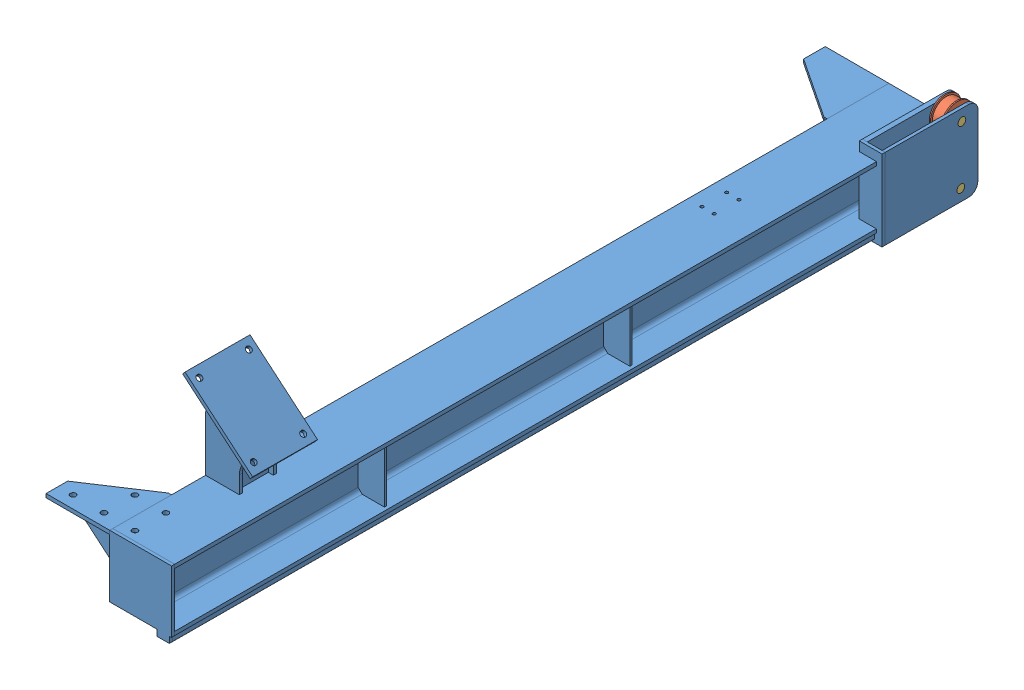
SolidWorks assembly 伸缩内壁装配, configuration 默认. Lengths in mm.
Overall size (424 557.37 2597.83).
9 component instances, 4 part files, 17 mates.
Components (placement in the parent):
- 提升侧内臂-1: 提升侧内臂 [默认<按加工>] at (318.4513 -276.1929 3310.3248) x (1 0 0) z (0 0.003262 0.999995) size (424 530 2590)
- 内套走轮-1: 内套走轮 [默认] at (404.5125 -377.4278 785.6415) x (0 -0.991423 -0.130691) z (0 -0.130691 0.991423) size (100 42 100)
- 内套走轮-2: 内套走轮 [默认] at (403.9866 -191.4386 782.0349) x (0 -0.979148 -0.203148) z (0 -0.203148 0.979148) size (100 42 100)
- 内套轮轴-1: 内套轮轴 [默认] at (158.6099 685.9764 -510.7484) x (1 0 0) z (0 -0.203148 0.979148) size (74 25.13 25.13)
- 内套轮轴-2: 内套轮轴 [默认] at (158.6099 528.967 -486.9912) x (1 0 0) z (0 -0.225215 0.974309) size (74 25.13 25.13)
- deep groove ball bearings gb-1: deep groove ball bearings gb [Rolling bearings 16005 GB 276-94] at (385.9866 -191.4386 782.0349) x (1 0 0) z (0 -0.203148 0.979148) size (8 47 47)
- deep groove ball bearings gb-2: deep groove ball bearings gb [Rolling bearings 16005 GB 276-94] at (418.5125 -377.4278 785.6415) x (1 0 0) z (0 -0.130691 0.991423) size (8 47 47)
- deep groove ball bearings gb-3: deep groove ball bearings gb [Rolling bearings 16005 GB 276-94] at (386.5125 -377.4278 785.6415) x (1 0 0) z (0 -0.130691 0.991423) size (8 47 47)
- deep groove ball bearings gb-4: deep groove ball bearings gb [Rolling bearings 16005 GB 276-94] at (417.9866 -191.4386 782.0349) x (1 0 0) z (0 -0.203148 0.979148) size (8 47 47)
Mates (geometry in assembly coordinates):
- 平行1: parallel: plane of 提升侧内臂-1 through (426.4513 -714.0533 1031.7408) normal (-1 0 0); plane of 内套走轮-2 through (422.9866 -168.4286 786.8089) normal (1 0 0)
- 平行2: parallel: plane of 提升侧内臂-1 through (426.4513 -714.0533 1031.7408) normal (-1 0 0); plane of 内套走轮-1 through (423.5125 -354.1294 788.7128) normal (1 0 0)
- 同心10: concentric: cylinder of 提升侧内臂-1 through (327.0959 -377.4278 785.6415) axis (1 0 0) radius 12.5; cylinder of 内套轮轴-2 through (326.9056 -377.4278 785.6415) axis (1 0 0) radius 12.5673
- 同心2: concentric: cylinder of 内套走轮-2 through (453.7136 -191.4386 782.0349) axis (1 0 0) radius 23.5; cylinder of deep groove ball bearings gb-1 through (377.276 -191.4386 782.0349) axis (-1 0 0) radius 23.5
- 重合4: coincident: plane of 内套走轮-2 through (389.9866 -173.3244 785.7931) normal (-1 0 0); plane of deep groove ball bearings gb-1 through (389.9866 -168.4286 786.8089) normal (1 0 0)
- 同心3: concentric: cylinder of 内套走轮-2 through (453.7136 -191.4386 782.0349) axis (1 0 0) radius 23.5; cylinder of deep groove ball bearings gb-4 through (409.276 -191.4386 782.0349) axis (-1 0 0) radius 23.5
- 重合5: coincident: plane of 内套走轮-2 through (413.9866 -173.3244 785.7931) normal (1 0 0); plane of deep groove ball bearings gb-4 through (413.9866 -168.4286 786.8089) normal (-1 0 0)
- 同心4: concentric: cylinder of 内套轮轴-1 through (326.9056 -191.4386 782.0349) axis (1 0 0) radius 12.5673; cylinder of deep groove ball bearings gb-4 through (411.0153 -191.4386 782.0349) axis (-1 0 0) radius 12.5
- 同心5: concentric: moEndPointRef_w of 内套走轮-2; cylinder of deep groove ball bearings gb-4 through (411.0153 -191.4386 782.0349) axis (-1 0 0) radius 12.5
- 平行3: parallel: cylinder of 内套轮轴-1 through (326.9056 -191.4386 782.0349) axis (1 0 0) radius 12.5673; cylinder of deep groove ball bearings gb-4 through (411.0153 -191.4386 782.0349) axis (-1 0 0) radius 12.5
- 同心7: concentric: cylinder of 提升侧内臂-1 through (327.0959 -191.4386 782.0349) axis (1 0 0) radius 12.5; cylinder of 内套轮轴-1 through (326.9056 -191.4386 782.0349) axis (1 0 0) radius 12.5673
- 同心8: concentric: cylinder of 内套走轮-1 through (454.2394 -377.4278 785.6415) axis (1 0 0) radius 23.5; cylinder of deep groove ball bearings gb-3 through (377.8018 -377.4278 785.6415) axis (-1 0 0) radius 23.5
- 同心9: concentric: cylinder of 内套走轮-1 through (454.2394 -377.4278 785.6415) axis (1 0 0) radius 23.5; cylinder of deep groove ball bearings gb-2 through (409.8018 -377.4278 785.6415) axis (-1 0 0) radius 23.5
- 重合7: coincident: plane of 内套走轮-1 through (414.5125 -359.0865 788.0593) normal (1 0 0); plane of deep groove ball bearings gb-2 through (414.5125 -354.1294 788.7128) normal (-1 0 0)
- 重合8: coincident: plane of 内套走轮-1 through (390.5125 -359.0865 788.0593) normal (-1 0 0); plane of deep groove ball bearings gb-3 through (390.5125 -354.1294 788.7128) normal (1 0 0)
- 同心11: concentric: cylinder of 内套轮轴-2 through (326.9056 -377.4278 785.6415) axis (1 0 0) radius 12.5673; cylinder of deep groove ball bearings gb-2 through (411.5411 -377.4278 785.6415) axis (-1 0 0) radius 12.5
- 重合9: coincident: plane of 提升侧内臂-1 through (436.4513 -714.0533 1031.7408) normal (1 0 0); plane of 内套轮轴-2 through (436.4513 -377.4278 785.6415) normal (1 0 0)
